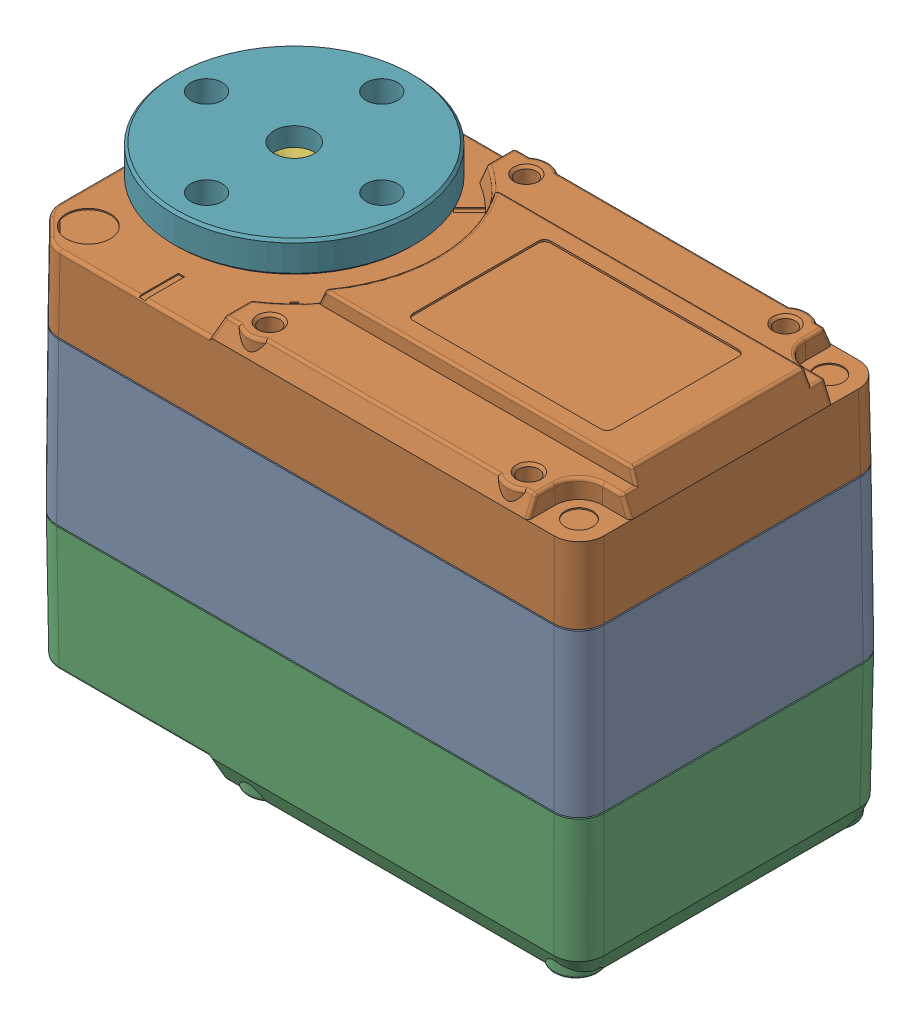
SolidWorks assembly ST3215_2, configuration Default. Lengths in mm.
Overall size (45.22 37.8 24.72).
7 component instances, 7 part files, 0 mates.
Components (placement in the parent):
- ZK_122-1: ZK_122 [Default] at (-27.959 54.9502 21.9834) size (45.22 13.9 24.72)
- SG-ZIJI_15-1: SG-ZIJI_15 [Default] at (-27.959 54.9502 21.9834) size (45 9.77 24.5)
- XG-ZIJI_16-1: XG-ZIJI_16 [Default] at (-27.959 54.9502 21.9834) size (45.22 14.1 24.72)
- MOTOR-1723_3-1: MOTOR-1723_3 [Default] at (-27.959 32.1002 20.7334) x (0 0 -1) z (1 0 0) size (17.05 30.5 17.05)
- PCB-CHAZUO_92-1: PCB-CHAZUO_92 [Default] at (-27.959 54.9502 21.9834) size (28.8 7.2 21.1)
- GE_27-1: GE_27 [Default] at (-53.459 48.9502 21.9834) x (1 0 0) z (0 -1 0) size (17.6 17.59 18.3)
- 金属舵盘（驱动）-1: 金属舵盘（驱动） [Default] at (-63.459 37.5502 21.9834) size (19.2 4.5 19.2)
